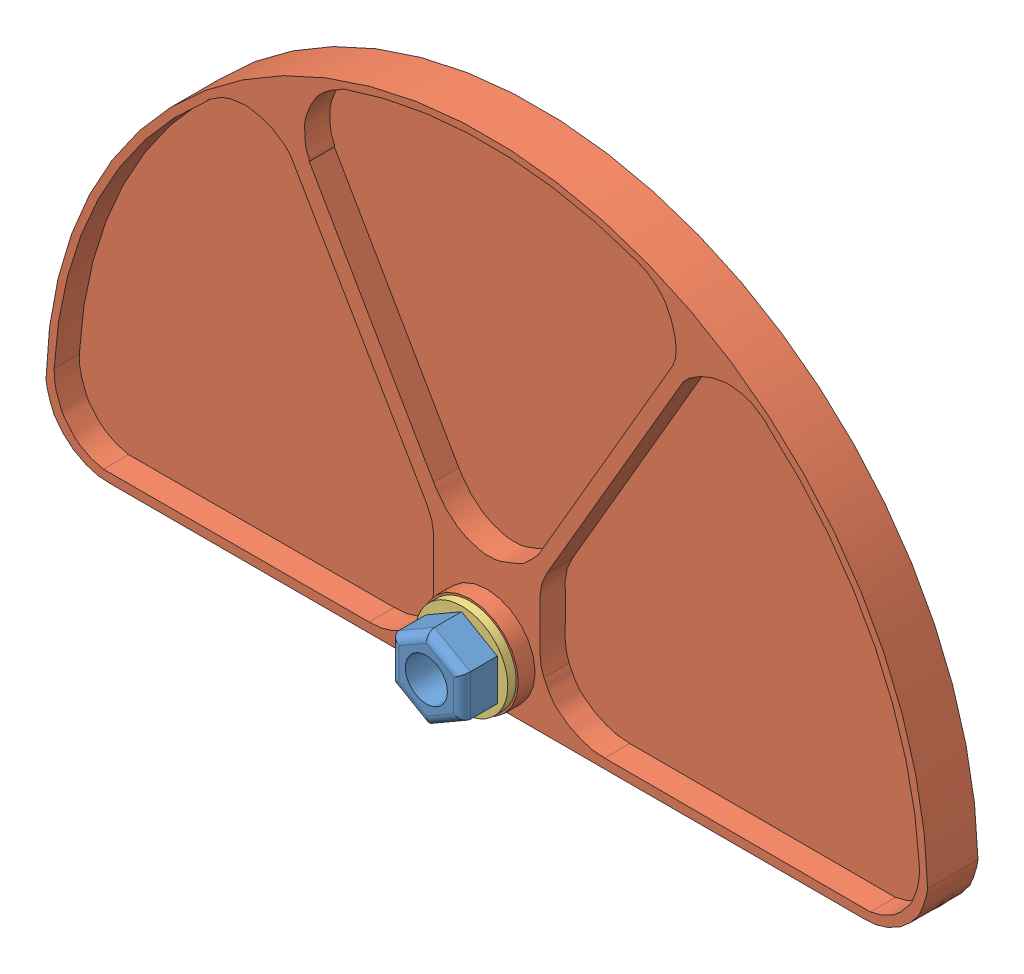
SolidWorks assembly Pirce0_Roeu2, configuration Défaut. Lengths in mm.
Overall size (209.95 119.37 30.4).
3 component instances, 3 part files, 5 mates.
Components (placement in the parent):
- Pièce2_EcrouBras-1: Pièce2_EcrouBras [Défaut] at origin size (17 19.63 8.4)
- Pièce1_Roue-1: Pièce1_Roue [Défaut] at (0 0 -10.4) x (-1 0 0) z (0 0 -1) size (209.95 116.72 20)
- Pièce1_Rendelle-1: Pièce1_Rendelle [Défaut] at (0 0 -8.4) x (-0.923728 -0.383049 0) z (0 0 -1) size (22 22 2)
Mates (geometry in assembly coordinates):
- Coïncidente2: coincident anti-aligned: plane of Pièce2_EcrouBras-1 through (0 0 -8.4) normal (0 0 -1); plane of Pièce1_Rendelle-1 through (0 0 -8.4) normal (0 0 1)
- Coaxiale2: concentric aligned: cylinder of Pièce2_EcrouBras-1 through (0 0 -8.4) axis (0 0 1) radius 5; cylinder of Pièce1_Rendelle-1 through (0 0 -10.4) axis (0 0 1) radius 5
- Coaxiale3: concentric aligned: cylinder of Pièce2_EcrouBras-1 through (0 0 -8.4) axis (0 0 1) radius 5; cylinder of Pièce1_Roue-1 through (0 0 -45.4) axis (0 0 1) radius 5
- Coïncidente3: coincident anti-aligned: plane of Pièce1_Roue-1 through (0 0 -10.4) normal (0 0 1); plane of Pièce1_Rendelle-1 through (0 0 -10.4) normal (0 0 -1)
- Coïncidente4: coincident aligned: plane of Pièce1_Roue-1; plane of assembly
